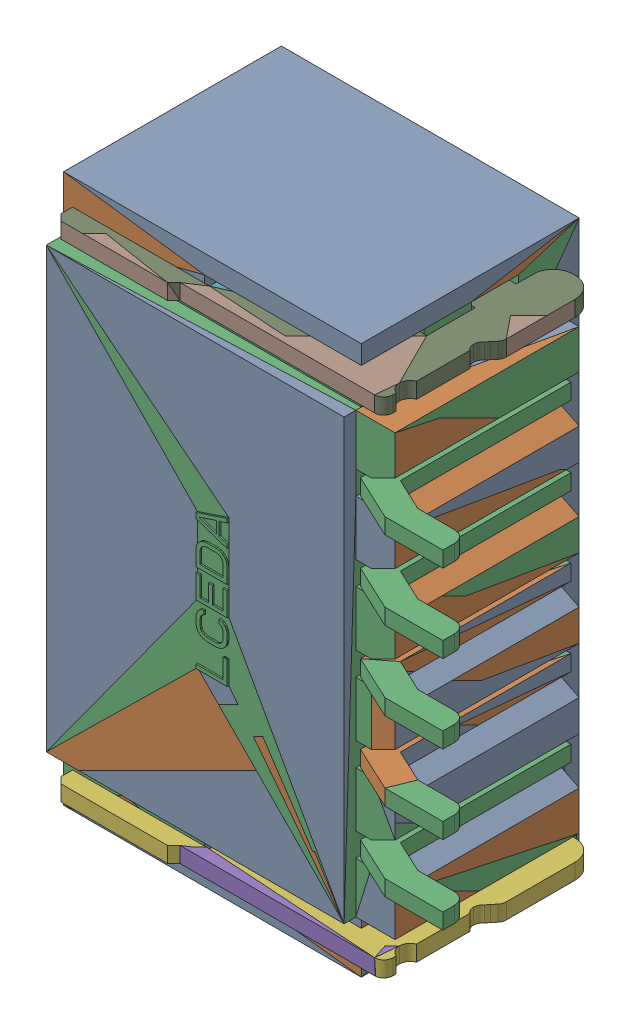
SolidWorks assembly CN4, configuration Défaut. Lengths in mm.
Overall size (5.2 7 3.14).
9 component instances, 6 part files, 0 mates.
Components (placement in the parent):
- A1002WR-S-5P-1: A1002WR-S-5P [Défaut] at (9.95 -36.769 -0.4818) x (0 1 0) z (0 0 -1) size (7 5.2 3.14)
- A1002WR-S-5P-2: A1002WR-S-5P [Défaut] at (9.95 -36.769 -0.4818) x (0 1 0) z (0 0 -1) size (7 5.2 3.14)
- A1002WR-S-5P_858-1: A1002WR-S-5P_858 [Défaut] at (9.95 -36.769 -0.4818) x (0 1 0) z (0 0 -1) size (7 5.2 3.14)
- A1002WR-S-5P_860-1: A1002WR-S-5P_860 [Défaut] at (9.95 -36.769 -0.4818) x (0 1 0) z (0 0 -1) size (0.2 4.22 2.68)
- A1002WR-S-5P_860-2: A1002WR-S-5P_860 [Défaut] at (9.95 -36.769 -0.4818) x (0 1 0) z (0 0 -1) size (0.2 4.22 2.68)
- A1002WR-S-5P_863-1: A1002WR-S-5P_863 [Défaut] at (9.95 -36.769 -0.4818) x (0 1 0) z (0 0 -1) size (0.2 4.22 2.68)
- A1002WR-S-5P_865-1: A1002WR-S-5P_865 [Défaut] at (9.95 -36.769 -0.4818) x (0 1 0) z (0 0 -1) size (0.2 4.22 2.68)
- A1002WR-S-5P_865-2: A1002WR-S-5P_865 [Défaut] at (9.95 -36.769 -0.4818) x (0 1 0) z (0 0 -1) size (0.2 4.22 2.68)
- A1002WR-S-5P_868-1: A1002WR-S-5P_868 [Défaut] at (9.95 -36.769 -0.4818) x (0 1 0) z (0 0 -1) size (0.2 4.22 2.68)
